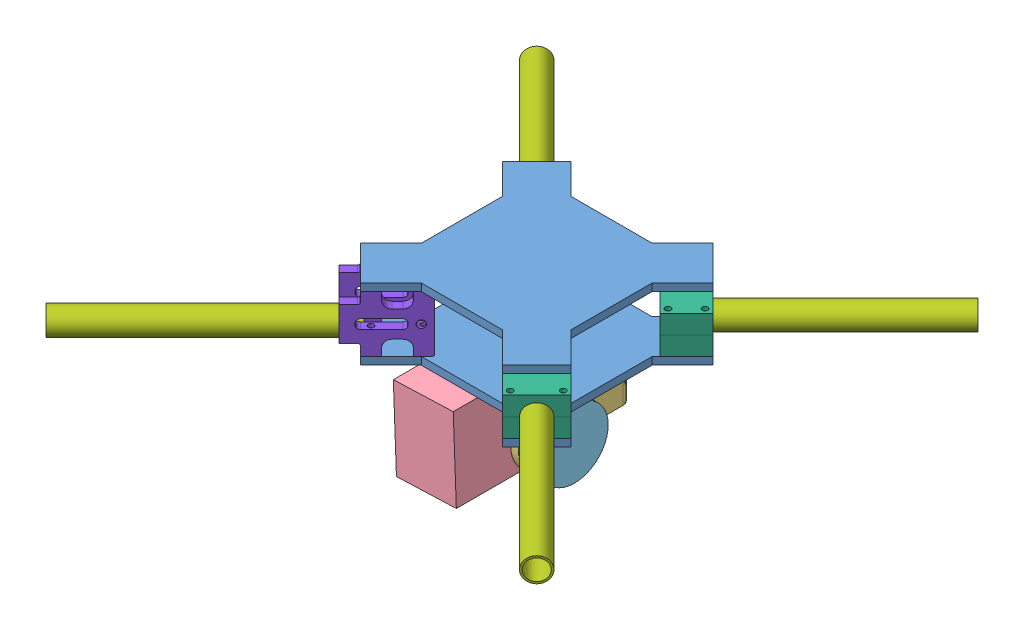
SolidWorks assembly Assem1, configuration Default. Lengths in mm.
Overall size (265.38 100.61 263.26).
23 component instances, 9 part files, 23 mates.
Components (placement in the parent):
- FPV_Body-1: FPV_Body [Default] at (-29.569 35.1111 97.2769) size (112.53 4 112.53)
- FPV_Body-2: FPV_Body [Default] at (-29.569 69.1111 97.2769) size (112.53 4 112.53)
- Assem2-1: Assem2 [Default] at (-54.7426 -26.8706 65.9777) x (0.999297 0.037501 0) z (0 0 1) size (63.98 62.12 80)
  - gimbal part 1-2: gimbal part 1 [Default] at (0 26 -7) size (24 38 70)
  - gimbal part 2-1: gimbal part 2 [Default] at (0 26 -7) x (0 0 -1) z (-0.037501 -0.999297 0) size (60 58 36)
  - gopro-1: gopro [Default] at (-11.9523 46 7) x (0 0 1) z (0 1 0) size (62 32 44)
  - gimbal part 3-1: gimbal part 3 [Default] at (43.9691 24.35 31) x (-0.999297 0.037501 0) z (0 0 -1) size (50 54 36)
- Cụm-gá-1: Cụm-gá [Default] at (25.7223 75.6726 142.0093) x (-0.707107 0 0.707107) z (0 -1 0) size (26 120 20)
  - FPV_do-ga-1: FPV_do-ga [Default] at (-5.5337 4.1589 26.5614) size (26 20 10)
  - FPV_Arm-1: FPV_Arm [Default] at (7.4663 -95.8411 26.5614) size (13 120 13)
  - FPV_do-ga-2: FPV_do-ga [Default] at (-5.5337 24.1589 26.5614) x (1 0 0) z (0 0 -1) size (26 20 10)
- Cụm-gá-3: Cụm-gá [Default] at (-84.8603 75.6726 52.5446) x (0.707107 0 -0.707107) z (0 -1 0) size (26 120 20)
  - FPV_do-ga-1: FPV_do-ga [Default] at (-5.5337 4.1589 26.5614) size (26 20 10)
  - FPV_Arm-1: FPV_Arm [Default] at (7.4663 -95.8411 26.5614) size (13 120 13)
  - FPV_do-ga-2: FPV_do-ga [Default] at (-5.5337 24.1589 26.5614) x (1 0 0) z (0 0 -1) size (26 20 10)
- Cụm-gá-4: Cụm-gá [Default] at (25.7223 22.5497 52.5446) x (-0.707107 0 -0.707107) z (0 1 0) size (26 120 20)
  - FPV_do-ga-1: FPV_do-ga [Default] at (-5.5337 4.1589 26.5614) size (26 20 10)
  - FPV_Arm-1: FPV_Arm [Default] at (7.4663 -95.8411 26.5614) size (13 120 13)
  - FPV_do-ga-2: FPV_do-ga [Default] at (-5.5337 24.1589 26.5614) x (1 0 0) z (0 0 -1) size (26 20 10)
- Do_ga_xin-1: Do_ga_xin [Default] at (-62.498 39.1111 118.8922) x (-0.707107 0 0.707107) z (-0.707107 0 -0.707107) size (36 30 5)
- Do_ga_xin-2: Do_ga_xin [Default] at (-47.6487 39.1111 133.7414) x (-0.707107 0 0.707107) z (-0.707107 0 -0.707107) size (36 30 5)
- noi_ga-2: noi_ga [Default] at (-66.0335 54.1111 122.4277) x (0.5 -0.707107 -0.5) z (-0.5 -0.707107 0.5) size (5 16 5)
- FPV_Arm-1: FPV_Arm [Default] at (-76.7587 45.6111 142.3453) x (0.386375 -0.837514 0.386375) z (-0.592212 -0.546416 -0.592212) size (13 120 13)
Mates (geometry in assembly coordinates):
- Coincident1: coincident anti-aligned: plane of FPV_Body-1 through (-29.569 39.1111 97.2769) normal (0 1 0); plane of Cụm-gá-4/FPV_do-ga-1 through (12.5523 39.1111 73.5404) normal (0 -1 0)
- Coincident5: coincident anti-aligned: plane of FPV_Body-1 through (-29.569 39.1111 97.2769) normal (0 1 0); plane of Cụm-gá-4/FPV_do-ga-1 through (12.5523 39.1111 73.5404) normal (0 -1 0)
- Coincident6: coincident aligned: plane of FPV_Body-1 through (17.502 35.1111 50.2059) normal (0.707107 0 -0.707107); plane of Cụm-gá-4/FPV_do-ga-2 through (26.6944 49.1111 59.3983) normal (0.707107 0 -0.707107)
- Coincident7: coincident aligned: plane of FPV_Body-1 through (-38.7614 35.1111 88.0846) normal (-0.707107 0 -0.707107); plane of Cụm-gá-4/FPV_do-ga-1 through (-5.8325 49.1111 55.1556) normal (-0.707107 0 -0.707107)
- Coincident8: coincident anti-aligned: plane of FPV_Body-1 through (-29.569 39.1111 97.2769) normal (0 1 0); plane of Cụm-gá-1/FPV_do-ga-2 through (26.6944 39.1111 135.1556) normal (0 -1 0)
- Coincident9: coincident aligned: plane of FPV_Body-1 through (-38.7614 35.1111 106.4693) normal (-0.707107 0 0.707107); plane of Cụm-gá-1/FPV_do-ga-1 through (-5.8325 49.1111 139.3983) normal (-0.707107 0 0.707107)
- Coincident10: coincident aligned: plane of FPV_Body-1 through (17.502 35.1111 144.348) normal (0.707107 0 0.707107); plane of Cụm-gá-1/FPV_do-ga-2 through (26.6944 49.1111 135.1556) normal (0.707107 0 0.707107)
- Coincident16: coincident anti-aligned: plane of FPV_Body-1 through (-29.569 39.1111 97.2769) normal (0 1 0); plane of Cụm-gá-3/FPV_do-ga-2 through (-85.8325 39.1111 59.3983) normal (0 -1 0)
- Coincident17: coincident aligned: plane of FPV_Body-1 through (-38.7614 35.1111 106.4693) normal (-0.707107 0 0.707107); plane of Cụm-gá-3/FPV_do-ga-2 through (-85.8325 49.1111 59.3983) normal (-0.707107 0 0.707107)
- Coincident18: coincident aligned: plane of FPV_Body-1 through (-76.6401 35.1111 50.2059) normal (-0.707107 0 -0.707107); plane of Cụm-gá-3/FPV_do-ga-2 through (-85.8325 49.1111 59.3983) normal (-0.707107 0 -0.707107)
- Coincident19: coincident anti-aligned: plane of FPV_Body-1 through (-29.569 35.1111 97.2769) normal (0 -1 0); plane of Assem2-1/gimbal part 3-1 through (-13.7176 35.1111 86.9777) normal (0 1 0)
- Coincident20: coincident anti-aligned: plane of FPV_Body-1 through (-29.569 39.1111 97.2769) normal (0 1 0); plane of Do_ga_xin-1 through (-66.7406 39.1111 116.0637) normal (0 -1 0)
- Coincident21: coincident aligned: plane of FPV_Body-1 through (-38.7614 35.1111 88.0846) normal (-0.707107 0 -0.707107); plane of Do_ga_xin-1 through (-90.7822 68.1111 140.1054) normal (-0.707107 0 -0.707107)
- Coincident23: coincident anti-aligned: plane of FPV_Body-2 through (-29.569 69.1111 97.2769) normal (0 -1 0); plane of Do_ga_xin-1 through (-66.7406 69.1111 116.0637) normal (0 1 0)
- Coincident24: coincident aligned: plane of FPV_Body-2 through (-76.6401 69.1111 144.348) normal (-0.707107 0 0.707107); plane of Do_ga_xin-1 through (-82.297 69.1111 138.6912) normal (-0.707107 0 0.707107)
- Coincident25: coincident aligned: plane of FPV_Body-2 through (-38.7614 69.1111 88.0846) normal (-0.707107 0 -0.707107); plane of Do_ga_xin-1 through (-90.7822 68.1111 140.1054) normal (-0.707107 0 -0.707107)
- Coincident30: coincident aligned: plane of FPV_Body-1 through (-20.3766 35.1111 106.4693) normal (0.707107 0 0.707107); plane of Do_ga_xin-2 through (-72.3975 68.1111 158.4902) normal (0.707107 0 0.707107)
- Coincident31: coincident anti-aligned: plane of FPV_Body-1 through (-29.569 39.1111 97.2769) normal (0 1 0); plane of Do_ga_xin-2 through (-51.8914 39.1111 130.913) normal (0 -1 0)
- Coincident32: coincident: line of FPV_Body-1 through (-67.4477 35.1111 153.5404) axis (-0.707107 0 -0.707107); plane of Do_ga_xin-2 through (-67.4477 44.1111 153.5404) normal (-0.707107 0 0.707107)
- Coincident33: coincident anti-aligned: plane of Do_ga_xin-2 through (-75.933 68.1111 154.9546) normal (-0.707107 0 -0.707107); plane of noi_ga-2 through (-54.7198 54.1111 133.7414) normal (0.707107 0 0.707107)
- Concentric1: concentric anti-aligned: cylinder of Do_ga_xin-1 through (-69.569 54.1111 118.8922) axis (0.707107 0 0.707107) radius 2; cylinder of noi_ga-2 through (-54.7198 54.1111 133.7414) axis (-0.707107 0 -0.707107) radius 2
- Tangent1: tangent anti-aligned: plane of FPV_Body-1 through (-29.569 39.1111 97.2769) normal (0 1 0); cylinder of FPV_Arm-1 through (-161.6115 45.6111 227.1981) axis (0.707107 0 -0.707107) radius 6.5
- Tangent2: tangent anti-aligned: plane of Do_ga_xin-1 through (-87.2467 68.1111 143.6409) normal (0.707107 0 0.707107); cylinder of FPV_Arm-1 through (-161.6115 45.6111 227.1981) axis (0.707107 0 -0.707107) radius 6.5
